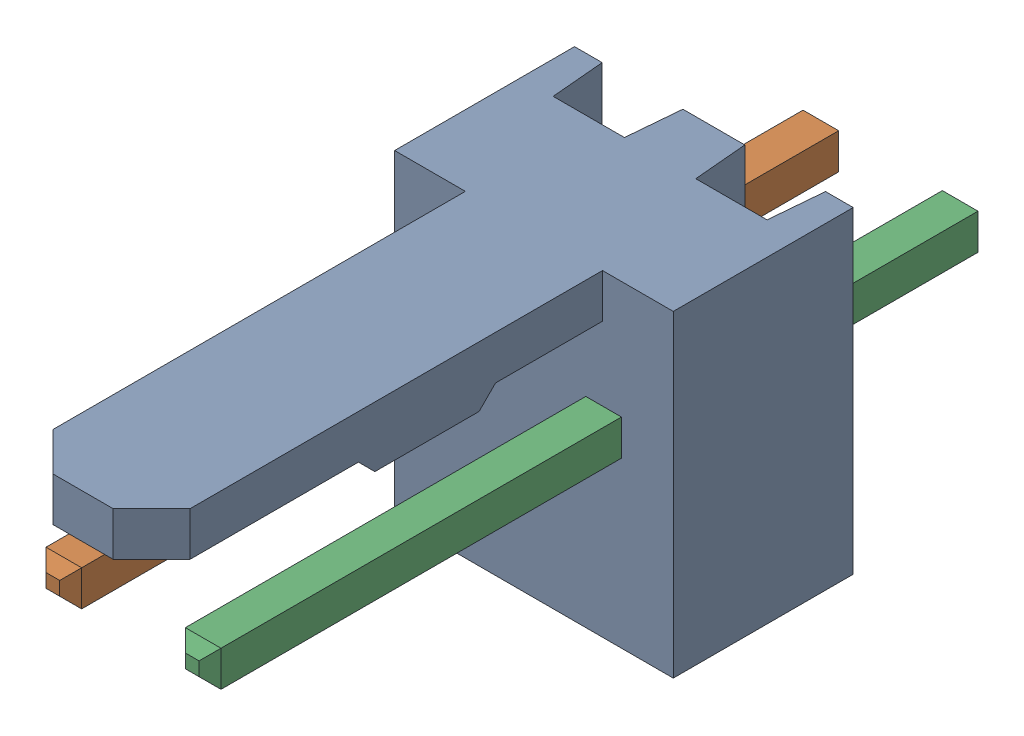
SolidWorks assembly Molex PCB 2 pin v2, configuration Predeterminado. Lengths in mm.
Overall size (5.08 5.79 14.92).
3 component instances, 2 part files, 0 mates.
Components (placement in the parent):
- BASE9710016_1-1: BASE9710016_1 [Predeterminado] at (2.54 2.895 -8.22) size (5.08 5.79 11.5)
- PINO9710016_1-1: PINO9710016_1 [Predeterminado] at (1.27 3.325 -0.72) size (0.65 0.65 14.2)
- PINO9710016_1-2: PINO9710016_1 [Predeterminado] at (3.81 3.325 -0.72) size (0.65 0.65 14.2)
